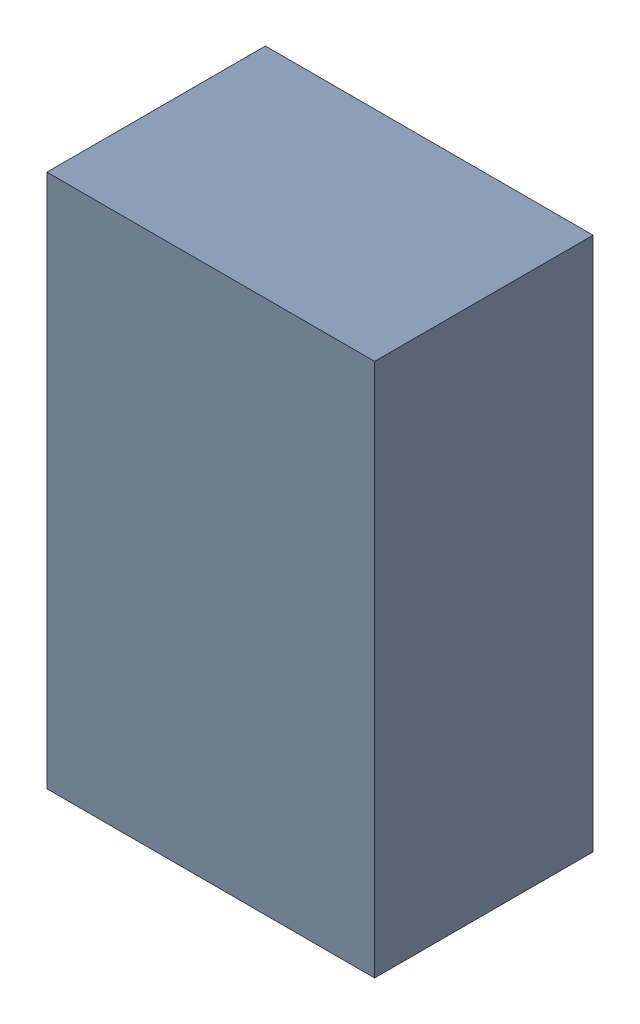
SolidWorks assembly Q301_2PCB, configuration Default. Lengths in mm.
Overall size (1.35 2.2 0.9).
2 component instances, 1 part files, 0 mates.
Components (placement in the parent):
- 846485600-1: 846485600 [Default] at (144.8 94.4 0.1) size (1.35 2.2 0.9)
  - Extruded_45-1: Extruded_45 [Default] at origin size (1.35 2.2 0.9)
